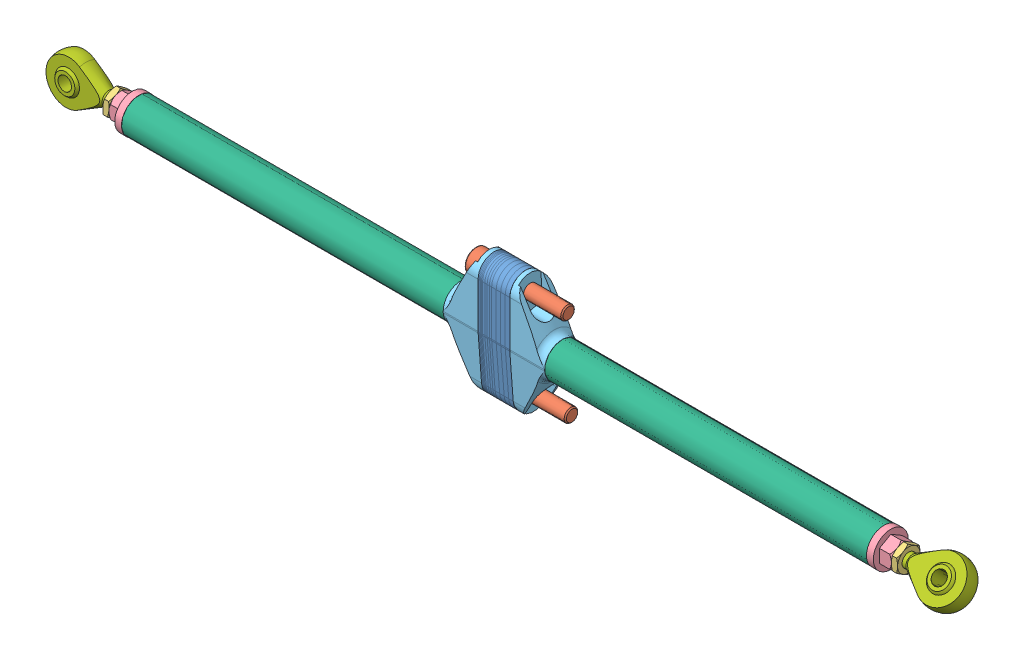
SolidWorks assembly LustroPUTM-S-SS-SS-TRS-Assembly, configuration Domyślna. Lengths in mm.
Overall size (405.25 54.72 22.34).
24 component instances, 7 part files, 58 mates.
Components (placement in the parent):
- LustroPUTM-S-Shims-1: LustroPUTM-S-Shims [1mm] at (163.6234 0 0) x (0 0.999297 0.0375) z (1 0 0) size (53.32 15.5 1)
- LustroPUTM-S-Shims-2: LustroPUTM-S-Shims [1mm] at (164.6234 0 0) x (0 0.999297 0.0375) z (1 0 0) size (53.32 15.5 1)
- LustroPUTM-S-Shims-3: LustroPUTM-S-Shims [1mm] at (165.6234 0 0) x (0 0.999297 0.0375) z (1 0 0) size (53.32 15.5 1)
- LustroPUTM-S-Shims-4: LustroPUTM-S-Shims [1mm] at (166.6234 0 0) x (0 0.999297 0.0375) z (1 0 0) size (53.32 15.5 1)
- LustroPUTM-S-Shims-5: LustroPUTM-S-Shims [2mm] at (168.6234 0 0) x (0 0.999297 0.0375) z (1 0 0) size (53.32 15.5 2)
- LustroPUTM-S-Shims-6: LustroPUTM-S-Shims [2mm] at (170.6234 0 0) x (0 0.999297 0.0375) z (1 0 0) size (53.32 15.5 2)
- LustroPUTM-S-Shims-7: LustroPUTM-S-Shims [2mm] at (172.6234 0 0) x (0 0.999297 0.0375) z (1 0 0) size (53.32 15.5 2)
- LustroPUTM-S-Shims-8: LustroPUTM-S-Shims [2mm] at (174.6234 0 0) x (0 0.999297 0.0375) z (1 0 0) size (53.32 15.5 2)
- LustroPUTM-S-Shims-9: LustroPUTM-S-Shims [0,5mm] at (162.1234 0 0) x (0 0.999297 0.0375) z (1 0 0) size (53.32 15.5 0.5)
- LustroPUTM-S-Shims-10: LustroPUTM-S-Shims [0,5mm] at (162.6234 0 0) x (0 0.999297 0.0375) z (1 0 0) size (53.32 15.5 0.5)
- LustroPUTM-S-Shims-11: LustroPUTM-S-Shims [0,5mm] at (161.1234 0 0) x (0 0.999297 0.0375) z (1 0 0) size (53.32 15.5 0.5)
- LustroPUTM-S-Shims-12: LustroPUTM-S-Shims [0,5mm] at (161.6234 0 0) x (0 0.999297 0.0375) z (1 0 0) size (53.32 15.5 0.5)
- LustroPUTM-FT-FABORY_ISO912-1: LustroPUTM-FT-FABORY_ISO912 [M6x35 [07071.060.035]] at (152.6234 -19.9859 -0.75) x (-1 0 0) z (0 -0.003221 0.999995) size (41 10 10)
- LustroPUTM-FT-FABORY_ISO912-2: LustroPUTM-FT-FABORY_ISO912 [M6x35 [07071.060.035]] at (152.6234 19.9859 0.75) x (-1 0 0) z (0 -0.003221 0.999995) size (41 10 10)
- LustroPUTM-FT-FABORY_ISO4035-1: LustroPUTM-FT-FABORY_ISO4035 [M6 [11360.060.001]] at (-5.3 0 0) x (0 -0.995917 0.09027) z (1 0 0) size (11.55 10 2.7)
- LustroPUTM-FT-FABORY_ISO4035-2: LustroPUTM-FT-FABORY_ISO4035 [M6 [11360.060.001]] at (343.2468 0 0) x (0 -0.999984 0.005726) z (1 0 0) size (11.55 10 2.7)
- LustroPUTM-S-SS-SS-Insert-1: LustroPUTM-S-SS-SS-Insert [M6] at origin size (38.3 15.5 15.5)
- LustroPUTM-S-SS-SS-Insert-2: LustroPUTM-S-SS-SS-Insert [M6] at (335.2468 0 0) x (-1 0 0) z (0 0.005726 0.999984) size (38.3 15.5 15.5)
- LustroPUTM-S-SS-SS-Insert_shims_2-1: LustroPUTM-S-SS-SS-Insert_shims_2 [Domyślna] at (160.6234 0 0) x (0 0.999297 0.0375) z (0 -0.0375 0.999297) size (54 55.42 20.32)
- LustroPUTM-S-SS-SS-Insert_shims_2-2: LustroPUTM-S-SS-SS-Insert_shims_2 [Domyślna] at (174.6234 0 0) x (0 0.999297 0.0375) z (0 0.0375 -0.999297) size (54 55.42 20.32)
- LustroPUTM-S-SS-SS-Tie_rod-1: LustroPUTM-S-SS-SS-Tie_rod [Domyślna] at (190.0468 0 0) x (0 0.999143 -0.041392) z (-1 0 0) size (15.5 15.5 142.2)
- LustroPUTM-S-SS-SS-Tie_rod-2: LustroPUTM-S-SS-SS-Tie_rod [Domyślna] at (145.2 0 0) x (0 0.495709 -0.868489) z (1 0 0) size (15.5 15.5 142.2)
- LustroPUTM-S-rodend-1: LustroPUTM-S-rodend [6mm] at (323.9475 0 0) x (0 0.689637 0.724156) z (0 0.724156 -0.689637) size (9 46 20)
- LustroPUTM-S-rodend-2: LustroPUTM-S-rodend [6mm] at (10.6961 0 0) x (-0.000112 -0.061627 -0.998099) z (0 0.998099 -0.061627) size (9 46 20)
Mates (geometry in assembly coordinates):
- Wspólnie1: coordinate: point of LustroPUTM-S-SS-SS-Insert-1
- Koncentryczne1: concentric anti-aligned: cylinder of LustroPUTM-S-SS-SS-Insert-1 through (3 0 0) axis (-1 0 0) radius 6.3; cylinder of LustroPUTM-S-SS-SS-Tie_rod-2 through (3 0 0) axis (1 0 0) radius 7.75
- Koncentryczne2: concentric aligned: cylinder of LustroPUTM-S-SS-SS-Insert_shims_2-1 through (145.2 0 0) axis (1 0 0) radius 6.3; cylinder of LustroPUTM-S-SS-SS-Tie_rod-2 through (3 0 0) axis (1 0 0) radius 6.35
- Wspólnie2: coincident anti-aligned: plane of LustroPUTM-S-SS-SS-Insert_shims_2-1 through (145.2 0 0) normal (-1 0 0); plane of LustroPUTM-S-SS-SS-Tie_rod-2 through (145.2 0 0) normal (1 0 0)
- Wspólnie3: coincident anti-aligned: plane of LustroPUTM-S-Shims-11 through (160.6234 0 0) normal (-1 0 0); plane of LustroPUTM-S-SS-SS-Insert_shims_2-1 through (160.6234 0 0) normal (1 0 0)
- Koncentryczne3: concentric aligned: circle of LustroPUTM-S-Shims-11; circle of LustroPUTM-S-SS-SS-Insert_shims_2-1
- Koncentryczne4: concentric aligned: circle of LustroPUTM-S-Shims-11; circle of LustroPUTM-S-SS-SS-Insert_shims_2-1
- Wspólnie4: coincident anti-aligned: plane of LustroPUTM-S-Shims-11 through (161.1234 0 0) normal (1 0 0); plane of LustroPUTM-S-Shims-12 through (161.1234 0 0) normal (-1 0 0)
- Koncentryczne5: concentric aligned: circle of LustroPUTM-S-Shims-11; circle of LustroPUTM-S-Shims-12
- Koncentryczne6: concentric aligned: circle of LustroPUTM-S-Shims-11; circle of LustroPUTM-S-Shims-12
- Wspólnie5: coincident anti-aligned: plane of LustroPUTM-S-Shims-9 through (161.6234 0 0) normal (-1 0 0); plane of LustroPUTM-S-Shims-12 through (161.6234 0 0) normal (1 0 0)
- Koncentryczne7: concentric aligned: circle of LustroPUTM-S-Shims-9; circle of LustroPUTM-S-Shims-12
- Koncentryczne8: concentric aligned: circle of LustroPUTM-S-Shims-9; circle of LustroPUTM-S-Shims-12
- Wspólnie6: coincident anti-aligned: plane of LustroPUTM-S-Shims-9 through (162.1234 0 0) normal (1 0 0); plane of LustroPUTM-S-Shims-10 through (162.1234 0 0) normal (-1 0 0)
- Koncentryczne9: concentric aligned: circle of LustroPUTM-S-Shims-9; circle of LustroPUTM-S-Shims-10
- Koncentryczne10: concentric aligned: circle of LustroPUTM-S-Shims-9; circle of LustroPUTM-S-Shims-10
- Wspólnie7: coincident anti-aligned: plane of LustroPUTM-S-Shims-1 through (162.6234 0 0) normal (-1 0 0); plane of LustroPUTM-S-Shims-10 through (162.6234 0 0) normal (1 0 0)
- Wspólnie8: coincident anti-aligned: plane of LustroPUTM-S-Shims-1 through (163.6234 0 0) normal (1 0 0); plane of LustroPUTM-S-Shims-2 through (163.6234 0 0) normal (-1 0 0)
- Wspólnie9: coincident anti-aligned: plane of LustroPUTM-S-Shims-2 through (164.6234 0 0) normal (1 0 0); plane of LustroPUTM-S-Shims-3 through (164.6234 0 0) normal (-1 0 0)
- Wspólnie10: coincident anti-aligned: plane of LustroPUTM-S-Shims-3 through (165.6234 0 0) normal (1 0 0); plane of LustroPUTM-S-Shims-4 through (165.6234 0 0) normal (-1 0 0)
- Koncentryczne11: concentric aligned: circle of LustroPUTM-S-Shims-1; circle of LustroPUTM-S-Shims-10
- Koncentryczne12: concentric aligned: circle of LustroPUTM-S-Shims-1; circle of LustroPUTM-S-Shims-12
- Koncentryczne13: concentric aligned: circle of LustroPUTM-S-Shims-1; circle of LustroPUTM-S-Shims-2
- Koncentryczne14: concentric aligned: circle of LustroPUTM-S-Shims-1; circle of LustroPUTM-S-Shims-2
- Koncentryczne15: concentric aligned: circle of LustroPUTM-S-Shims-2; circle of LustroPUTM-S-Shims-3
- Koncentryczne16: concentric aligned: circle of LustroPUTM-S-Shims-2; circle of LustroPUTM-S-Shims-3
- Koncentryczne17: concentric aligned: circle of LustroPUTM-S-Shims-3; circle of LustroPUTM-S-Shims-4
- Koncentryczne18: concentric aligned: circle of LustroPUTM-S-Shims-3; circle of LustroPUTM-S-Shims-4
- Wspólnie11: coincident anti-aligned: plane of LustroPUTM-S-Shims-4 through (166.6234 0 0) normal (1 0 0); plane of LustroPUTM-S-Shims-5 through (166.6234 0 0) normal (-1 0 0)
- Wspólnie12: coincident anti-aligned: plane of LustroPUTM-S-Shims-5 through (168.6234 0 0) normal (1 0 0); plane of LustroPUTM-S-Shims-6 through (168.6234 0 0) normal (-1 0 0)
- Wspólnie13: coincident anti-aligned: plane of LustroPUTM-S-Shims-6 through (170.6234 0 0) normal (1 0 0); plane of LustroPUTM-S-Shims-7 through (170.6234 0 0) normal (-1 0 0)
- Wspólnie14: coincident anti-aligned: plane of LustroPUTM-S-Shims-7 through (172.6234 0 0) normal (1 0 0); plane of LustroPUTM-S-Shims-8 through (172.6234 0 0) normal (-1 0 0)
- Koncentryczne19: concentric aligned: circle of LustroPUTM-S-Shims-4; circle of LustroPUTM-S-Shims-5
- Koncentryczne20: concentric aligned: circle of LustroPUTM-S-Shims-4; circle of LustroPUTM-S-Shims-5
- Koncentryczne21: concentric aligned: circle of LustroPUTM-S-Shims-5; circle of LustroPUTM-S-Shims-6
- Koncentryczne22: concentric aligned: circle of LustroPUTM-S-Shims-5; circle of LustroPUTM-S-Shims-6
- Koncentryczne23: concentric aligned: circle of LustroPUTM-S-Shims-6; circle of LustroPUTM-S-Shims-7
- Koncentryczne24: concentric aligned: circle of LustroPUTM-S-Shims-6; circle of LustroPUTM-S-Shims-7
- Koncentryczne25: concentric aligned: circle of LustroPUTM-S-Shims-7; circle of LustroPUTM-S-Shims-8
- Koncentryczne26: concentric aligned: circle of LustroPUTM-S-Shims-7; circle of LustroPUTM-S-Shims-8
- Wspólnie15: coincident anti-aligned: plane of LustroPUTM-S-Shims-8 through (174.6234 0 0) normal (1 0 0); plane of LustroPUTM-S-SS-SS-Insert_shims_2-2 through (174.6234 0 0) normal (-1 0 0)
- Koncentryczne27: concentric anti-aligned: circle of LustroPUTM-S-Shims-8; circle of LustroPUTM-S-SS-SS-Insert_shims_2-2
- Koncentryczne28: concentric aligned: circle of LustroPUTM-S-Shims-8; circle of LustroPUTM-S-SS-SS-Insert_shims_2-2
- Równolegle1: parallel aligned: plane of LustroPUTM-S-SS-SS-Insert-1 through (-5.3 -2.8868 -5) normal (0 0 -1); plane of LustroPUTM-S-SS-SS-Insert_shims_2-1 through (135.6234 -19.9859 -7.75) normal (0 0 -1)
- Wspólnie16: coincident anti-aligned: plane of LustroPUTM-S-SS-SS-Insert-2 through (332.2468 -6.3499 0.0364) normal (-1 0 0); plane of LustroPUTM-S-SS-SS-Tie_rod-1 through (332.2468 0 0) normal (1 0 0)
- Koncentryczne29: concentric anti-aligned: cylinder of LustroPUTM-S-SS-SS-Insert-2 through (332.2468 0 0) axis (1 0 0) radius 6.3; cylinder of LustroPUTM-S-SS-SS-Tie_rod-1 through (332.2468 0 0) axis (-1 0 0) radius 7.75
- Koncentryczne30: concentric aligned: cylinder of LustroPUTM-S-SS-SS-Insert_shims_2-2 through (190.0468 0 0) axis (-1 0 0) radius 6.3; cylinder of LustroPUTM-S-SS-SS-Tie_rod-1 through (332.2468 0 0) axis (-1 0 0) radius 7.75
- Wspólnie17: coincident anti-aligned: plane of LustroPUTM-S-SS-SS-Insert_shims_2-2 through (190.0468 0 0) normal (1 0 0); plane of LustroPUTM-S-SS-SS-Tie_rod-1 through (190.0468 0 0) normal (-1 0 0)
- Wspólnie18: coincident anti-aligned: plane of LustroPUTM-S-SS-SS-Insert-1 through (3 6.35 0) normal (1 0 0); plane of LustroPUTM-S-SS-SS-Tie_rod-2 through (3 0 0) normal (-1 0 0)
- Koncentryczne31: concentric anti-aligned: cylinder of LustroPUTM-FT-FABORY_ISO912-2 through (275.7823 19.9859 0.75) axis (1 0 0) radius 3; cylinder of LustroPUTM-S-SS-SS-Insert_shims_2-1 through (160.6234 19.9859 0.75) axis (-1 0 0) radius 3
- Wspólnie19: coincident anti-aligned: plane of LustroPUTM-FT-FABORY_ISO912-2 through (158.6234 14.986 0.7339) normal (1 0 0); plane of LustroPUTM-S-SS-SS-Insert_shims_2-1 through (158.6234 17.4877 0.6562) normal (-1 0 0)
- Koncentryczne32: concentric anti-aligned: cylinder of LustroPUTM-FT-FABORY_ISO912-1 through (275.7823 -19.9859 -0.75) axis (1 0 0) radius 3; cylinder of LustroPUTM-S-SS-SS-Insert_shims_2-1 through (160.6234 -19.9859 -0.75) axis (-1 0 0) radius 3
- Wspólnie20: coincident anti-aligned: plane of LustroPUTM-FT-FABORY_ISO912-1 through (158.6234 -24.9859 -0.7661) normal (1 0 0); plane of LustroPUTM-S-SS-SS-Insert_shims_2-1 through (158.6234 -17.4877 -0.6562) normal (-1 0 0)
- Koncentryczne36: concentric anti-aligned: cylinder of LustroPUTM-S-SS-SS-Insert-1 through (0 0 0) axis (-1 0 0) radius 3; cone of LustroPUTM-S-rodend-2 through (-10.3035 0 0) axis (1 0 0)
- Koncentryczne37: concentric aligned: cylinder of LustroPUTM-FT-FABORY_ISO4035-1 through (-8 0 0) axis (1 0 0) radius 3; cone of LustroPUTM-S-rodend-2 through (-10.3035 0 0) axis (1 0 0)
- Wspólnie23: coincident anti-aligned: plane of LustroPUTM-FT-FABORY_ISO4035-1 through (-5.3 0 0) normal (1 0 0); plane of LustroPUTM-S-SS-SS-Insert-1 through (-5.3 0 0) normal (-1 0 0)
- Wspólnie24: coincident anti-aligned: plane of LustroPUTM-FT-FABORY_ISO4035-2 through (340.5468 0 0) normal (-1 0 0); plane of LustroPUTM-S-SS-SS-Insert-2 through (340.5468 0 0) normal (1 0 0)
- Koncentryczne38: concentric anti-aligned: cylinder of LustroPUTM-FT-FABORY_ISO4035-2 through (340.5468 0 0) axis (1 0 0) radius 3; cone of LustroPUTM-S-SS-SS-Insert-2 through (340.0468 0 0) axis (-1 0 0)
